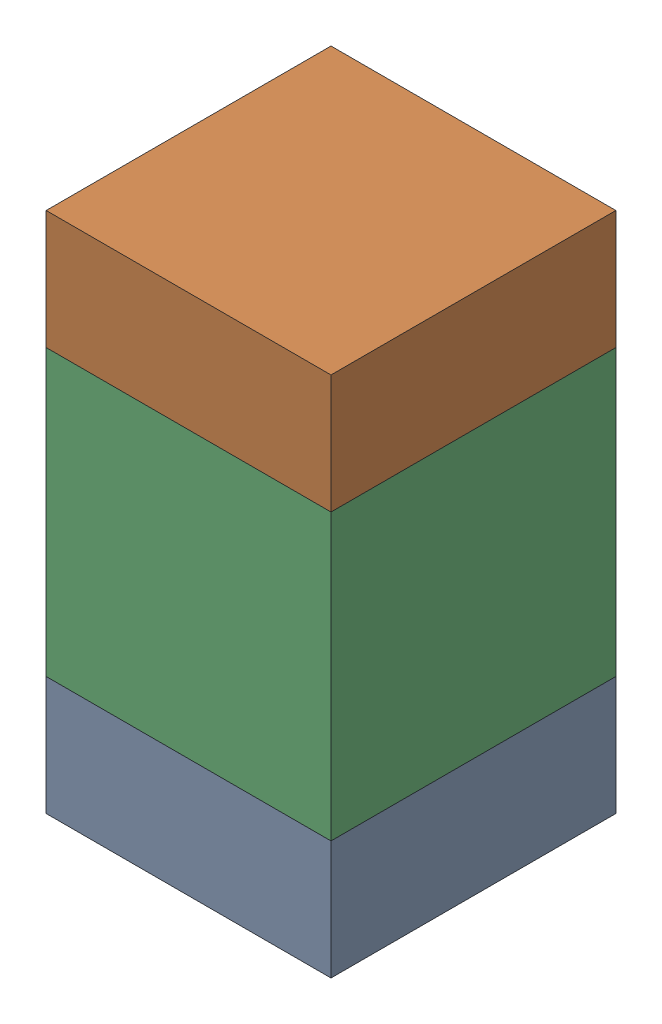
SolidWorks assembly C100_1PCB, configuration Default. Lengths in mm.
Overall size (0.6 1.1 0.6).
6 component instances, 2 part files, 0 mates.
Components (placement in the parent):
- 854785296-1: 854785296 [Default] at (107.7 120.875 0) size (0.6 0.25 0.6)
  - Extruded_10-1: Extruded_10 [Default] at origin size (0.6 0.25 0.6)
- 854785296-2: 854785296 [Default] at (107.7 121.725 0) size (0.6 0.25 0.6)
  - Extruded_10-1: Extruded_10 [Default] at origin size (0.6 0.25 0.6)
- 761606048-1: 761606048 [Default] at (107.7 121.3 0) size (0.6 0.6 0.6)
  - Extruded_9-1: Extruded_9 [Default] at origin size (0.6 0.6 0.6)
